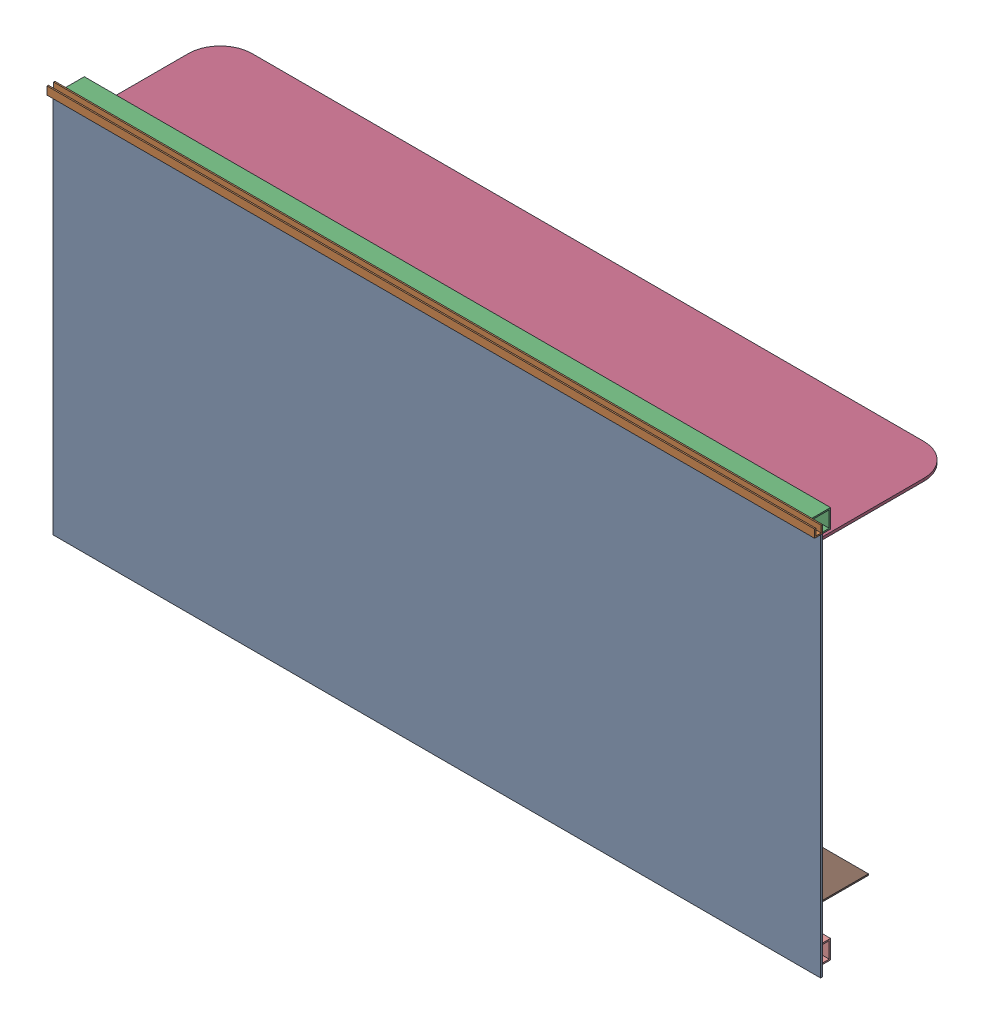
SolidWorks assembly FE-00004_, configuration Default. Lengths in mm.
Overall size (1828.8 933.45 374.65).
43 component instances, 16 part files, 0 mates.
Components (placement in the parent):
- FE-00004-01_-1: FE-00004-01_ [Default] at origin size (1828.8 914.4 4.76)
- FE-00004-05_-1: FE-00004-05_ [Default] at (-35.873 25.2374 19.5793) x (0 -1 0) z (1 0 0) size (19.05 19.05 1828.8)
- FE-00004-04_-1: FE-00004-04_ [Default] at (-10.473 22.3845 -16.9571) x (0 1 0) z (1 0 0) size (44.45 44.45 1778)
- FE-00004-06_-1: FE-00004-06_ [Default] at (39.0734 -21.4341 -19.8529) x (1 0 0) z (0 -1 0) size (1752.6 355.6 6.35)
- FE-00004-02_-1: FE-00004-02_ [Default] at (1729.427 -52.906 3.3994) x (0 0 1) z (-1 0 0) size (39.53 39.53 406.4)
  - FE-00004-02A_-1: FE-00004-02A_ [Default] at origin size (11.3 39.53 406.4)
  - FE-00004-02A_-2: FE-00004-02A_ [Default] at (-28.5213 28.5213 406.4) x (0 1 0) z (0 0 -1) size (11.3 39.53 406.4)
  - FE-00004-02C_-1: FE-00004-02C_ [Default] at (9.0309 7.3635 0) size (6.35 6.35 406.4)
- FE-00004-02_-2: FE-00004-02_ [Default] at (434.027 -52.906 3.3994) x (0 0 1) z (-1 0 0) size (39.53 39.53 406.4)
  - FE-00004-02A_-1: FE-00004-02A_ [Default] at origin size (11.3 39.53 406.4)
  - FE-00004-02A_-2: FE-00004-02A_ [Default] at (-28.5213 28.5213 406.4) x (0 1 0) z (0 0 -1) size (11.3 39.53 406.4)
  - FE-00004-02C_-1: FE-00004-02C_ [Default] at (9.0309 7.3635 0) size (6.35 6.35 406.4)
- FE-00004-03_-1: FE-00004-03_ [Default] at (1119.827 -52.906 3.3994) x (0 0 1) z (-1 0 0) size (39.53 39.53 482.6)
  - FE-00004-03A_-1: FE-00004-03A_ [Default] at origin size (11.3 39.53 482.6)
  - FE-00004-03B_-1: FE-00004-03B_ [Default] at (-28.5213 28.5213 482.6) x (0 1 0) z (0 0 -1) size (11.3 39.53 482.6)
  - FE-00004-03C_-1: FE-00004-03C_ [Default] at (9.0309 7.3635 0) size (6.35 6.35 482.6)
- FE-00004-08_-1: FE-00004-08_ [Default] at (539.4536 -2.9076 -281.5158) x (-0.844319 0.535841 0) z (0 0 1) size (39.43 54.56 203.2)
  - FE-00004-08A_-1: FE-00004-08A_ [Default] at (15.9508 35.5603 3.2618) x (0.535841 -0.844319 0) z (0 0 1) size (11.3 39.53 203.2)
  - FE-00004-08C_-1: FE-00004-08C_ [Default] at (45.8136 41.8195 3.2618) x (0.999872 0.016022 0) z (0 0 1) size (6.35 6.35 203.2)
  - FE-00004-08A_-2: FE-00004-08A_ [Default] at (24.7489 74.9242 206.4618) x (0.844319 0.535841 0) z (0 0 -1) size (11.3 39.53 203.2)
- FE-00004-08_-2: FE-00004-08_ [Default] at (1300.121 -85.4282 -281.5158) x (0.535841 0.844319 0) z (0 0 1) size (39.43 54.56 203.2)
  - FE-00004-08A_-1: FE-00004-08A_ [Default] at (15.9508 35.5603 3.2618) x (0.535841 -0.844319 0) z (0 0 1) size (11.3 39.53 203.2)
  - FE-00004-08C_-1: FE-00004-08C_ [Default] at (45.8136 41.8195 3.2618) x (0.999872 0.016022 0) z (0 0 1) size (6.35 6.35 203.2)
  - FE-00004-08A_-2: FE-00004-08A_ [Default] at (24.7489 74.9242 206.4618) x (0.844319 0.535841 0) z (0 0 -1) size (11.3 39.53 203.2)
- FE-00004-09_-1: FE-00004-09_ [Default] at (1278.4195 -52.6269 -273.7799) x (0 0 1) z (-1 0 0) size (303.65 152.4 3.18)
- FE-00004-09_-2: FE-00004-09_ [Default] at (481.8095 -52.6269 -273.7799) x (0 0 1) z (-1 0 0) size (303.65 152.4 3.18)
- FE-00004-04_-2: FE-00004-04_ [Default] at (1767.527 -863.8912 -19.6814) x (0 0 1) z (-1 0 0) size (44.45 44.45 1778)
- FE-00004-07_-1: FE-00004-07_ [Default] at (1234.127 -850.3335 -32.9171) x (0 -1 0) z (1 0 0) size (55.75 65.47 406.4)
  - FE-00004-07A_-1: FE-00004-07A_ [Default] at origin size (11.3 39.53 406.4)
  - FE-00004-07A_-2: FE-00004-07A_ [Default] at (15.9287 8.1335 0) x (0 -1 0) z (0 0 1) size (11.3 39.53 406.4)
  - FE-00004-07B_-1: FE-00004-07B_ [Default] at (10.4195 10.4195 406.4) x (0 -1 0) z (0 0 -1) size (11.3 39.53 406.4)
  - FE-00004-07C_-1: FE-00004-07C_ [Default] at (9.0309 31.5773 406.4) x (1 0 0) z (0 0 -1) size (6.35 6.35 406.4)
  - FE-00004-07A_-3: FE-00004-07A_ [Default] at (44.45 36.6548 406.4) x (1 0 0) z (0 0 -1) size (11.3 39.53 406.4)
  - FE-00004-07C_-2: FE-00004-07C_ [Default] at (52.4116 3.616 406.4) x (0.302716 -0.953081 0) z (0 0 -1) size (6.35 6.35 406.4)
- FE-00004-07_-2: FE-00004-07_ [Default] at (116.527 -850.3335 -32.9171) x (0 -1 0) z (1 0 0) size (55.75 65.47 406.4)
  - FE-00004-07A_-1: FE-00004-07A_ [Default] at origin size (11.3 39.53 406.4)
  - FE-00004-07A_-2: FE-00004-07A_ [Default] at (15.9287 8.1335 0) x (0 -1 0) z (0 0 1) size (11.3 39.53 406.4)
  - FE-00004-07B_-1: FE-00004-07B_ [Default] at (10.4195 10.4195 406.4) x (0 -1 0) z (0 0 -1) size (11.3 39.53 406.4)
  - FE-00004-07C_-1: FE-00004-07C_ [Default] at (9.0309 31.5773 406.4) x (1 0 0) z (0 0 -1) size (6.35 6.35 406.4)
  - FE-00004-07A_-3: FE-00004-07A_ [Default] at (44.45 36.6548 406.4) x (1 0 0) z (0 0 -1) size (11.3 39.53 406.4)
  - FE-00004-07C_-2: FE-00004-07C_ [Default] at (52.4116 3.616 406.4) x (0.302716 -0.953081 0) z (0 0 -1) size (6.35 6.35 406.4)
- FE-00004-10_-1: FE-00004-10_ [Default] at (1270.0794 -889.0981 -82.4689) x (1 0 0) z (0 1 0) size (406.4 203.2 3.17)
- FE-00004-10_-2: FE-00004-10_ [Default] at (152.4794 -889.0981 -82.4689) x (1 0 0) z (0 1 0) size (406.4 203.2 3.17)
